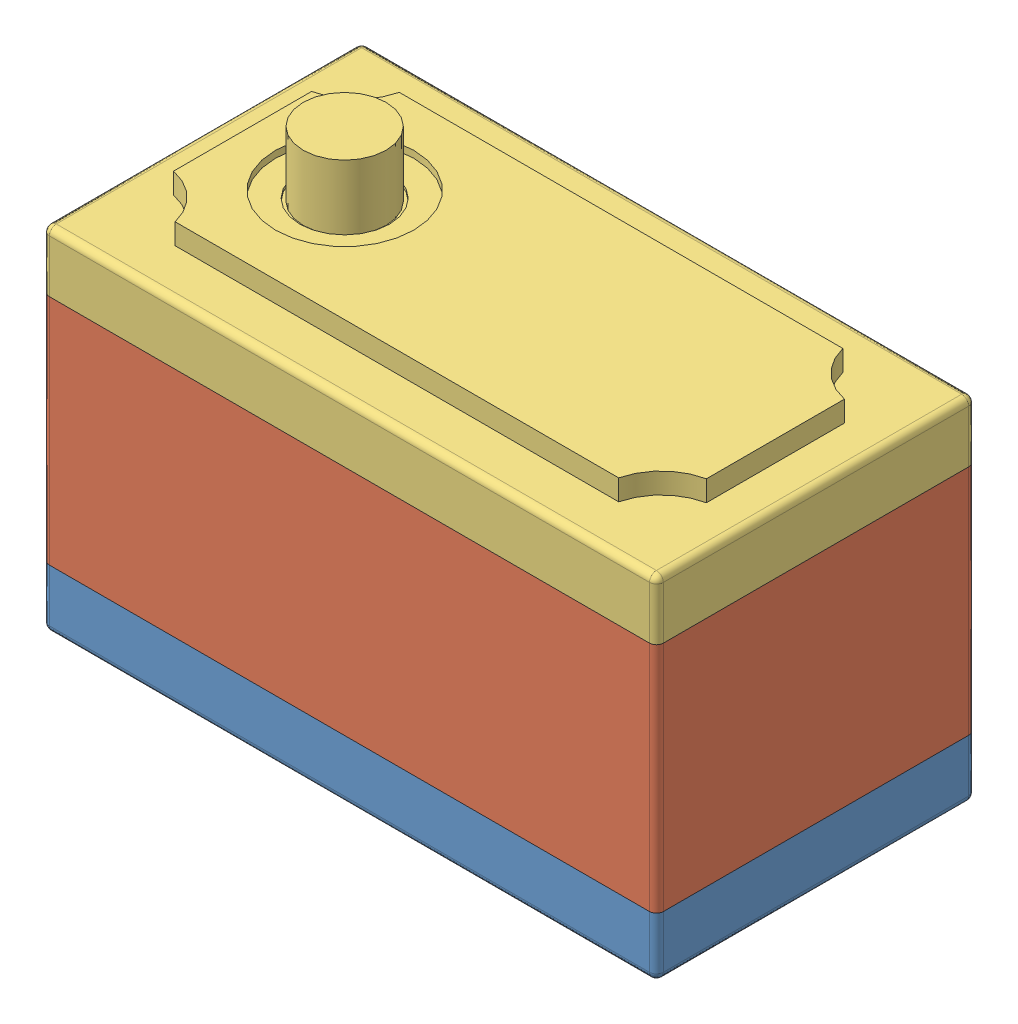
SolidWorks assembly YB-SD15M_LD, configuration Predeterminado. Lengths in mm.
Overall size (44.37 36.2 23.06).
3 component instances, 3 part files, 5 mates.
Components (placement in the parent):
- YB-SD15M-Bottom-Cover-LD-1: YB-SD15M-Bottom-Cover-LD [Predeterminado] at (-14.273 -0.1143 0) size (44.37 9.6 23.06)
- YB-SD15M-Middle-Cover-LD-1: YB-SD15M-Middle-Cover-LD [Predeterminado] at (-14.273 4.1857 0) size (44.37 16.8 23.06)
- YB-SD15M-Top-Cover-LD-1: YB-SD15M-Top-Cover-LD [Predeterminado] at (-14.273 25.2857 0) x (1 0 0) z (0 0 -1) size (44.37 9.8 23.06)
Mates (geometry in assembly coordinates):
- Coincidente1: coincident anti-aligned: plane of YB-SD15M-Bottom-Cover-LD-1 through (-14.273 4.1857 0) normal (0 1 0); plane of YB-SD15M-Middle-Cover-LD-1 through (-14.273 4.1857 0) normal (0 -1 0)
- Coincidente3: coincident aligned: line of YB-SD15M-Middle-Cover-LD-1 through (7.912 4.1857 -11.03) axis (0 0 1); line of YB-SD15M-Bottom-Cover-LD-1 through (7.912 4.1857 -11.03) axis (0 0 1)
- Coincidente4: coincident anti-aligned: plane of YB-SD15M-Middle-Cover-LD-1 through (-14.273 20.9857 0) normal (0 1 0); plane of YB-SD15M-Top-Cover-LD-1 through (-14.273 20.9857 0) normal (0 -1 0)
- Coincidente6: coincident anti-aligned: line of YB-SD15M-Middle-Cover-LD-1 through (-36.458 20.9857 -11.03) axis (0 0 1); line of YB-SD15M-Top-Cover-LD-1 through (-36.458 20.9857 11.03) axis (0 0 -1)
- Coincidente8: coincident aligned: line of YB-SD15M-Middle-Cover-LD-1 through (-35.958 20.9857 11.53) axis (1 0 0); line of YB-SD15M-Top-Cover-LD-1 through (-35.958 20.9857 11.53) axis (1 0 0)
